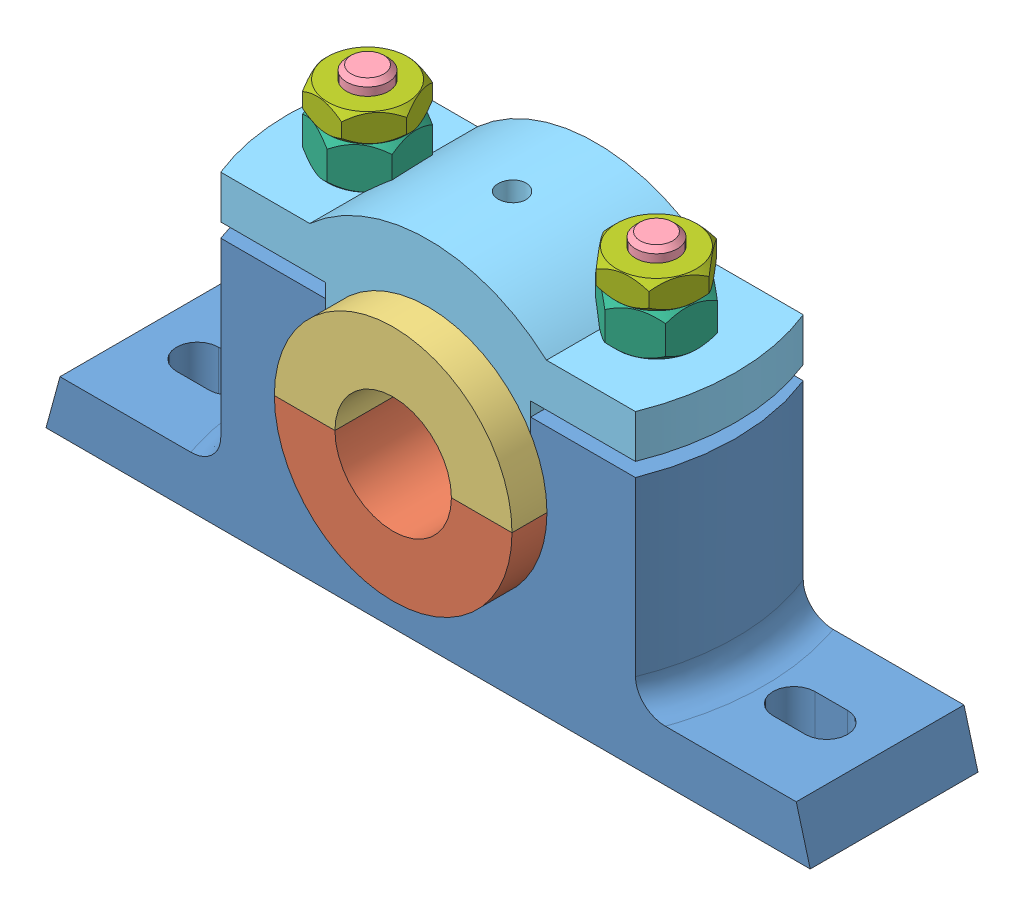
SolidWorks assembly Assem51, configuration Default. Lengths in mm.
Overall size (164 84 51).
10 component instances, 7 part files, 16 mates.
Components (placement in the parent):
- Part2-1: Part2 [Default] at (52.0479 67.0087 143.3422) size (164 54 36)
- Part432-2: Part432 [Default] at (26.5479 105.0087 168.8422) x (0 0 -1) z (-1 0 0) size (51 25.5 51)
- Part43-1: Part43 [Default] at (26.5479 105.0087 117.8422) x (0 0 1) z (-1 0 0) size (51 25.5 51)
- Part44-2: Part44 [Default] at (21.0479 151.0087 143.3422) x (-1 0 0) z (0 -1 0) size (19 19 82)
- Part4-1: Part4 [Default] at (52.0479 105.0087 143.3422) size (96 32 36)
- Part45-2: Part45 [Default] at (21.0479 137.7778 143.3422) x (-0.703417 0 0.710777) z (0 1 0) size (21.7 20.5 9)
- Part45-3: Part45 [Default] at (83.0479 137.7778 143.3422) x (0.703417 0 0.710777) z (0 -1 0) size (21.7 20.5 9)
- Part44-3: Part44 [Default] at (83.0479 151.0087 143.3422) x (-1 0 0) z (0 -1 0) size (19 19 82)
- Part46-1: Part46 [Default] at (21.0479 145.2778 143.3422) x (1 0 0) z (0 1 0) size (21.7 20.5 6)
- Part46-2: Part46 [Default] at (83.0479 145.2778 143.3422) x (-1 0 0) z (0 -1 0) size (21.7 20.5 6)
Mates (geometry in assembly coordinates):
- Lock1: lock: unknown of Part2-1; unknown of Part432-2
- Lock2: lock: unknown of Part2-1; unknown of Part432-2
- Lock5: lock: unknown of Part432-2; unknown of Part43-1
- Concentric6: concentric anti-aligned: circle of Part432-2; cylinder of Part43-1 through (52.0479 122.5087 143.3422) axis (0 1 0) radius 2.5
- Lock8: lock: unknown of Part2-1; unknown of Part44-2
- Concentric15: concentric aligned: cylinder of Part43-1 through (52.0479 105.0087 143.3422) axis (0 0 -1) radius 17.5; cylinder of Part4-1 through (52.0479 105.0087 161.3422) axis (0 0 -1) radius 19
- Concentric18: concentric aligned: cylinder of Part43-1 through (52.0479 105.0087 143.3422) axis (0 0 -1) radius 17.5; cylinder of Part4-1 through (52.0479 105.0087 161.3422) axis (0 0 -1) radius 19
- Concentric19: concentric aligned: cylinder of Part2-1 through (83.0479 121.0087 143.3422) axis (0 1 0) radius 4.5; cylinder of Part4-1 through (83.0479 133.2778 143.3422) axis (0 1 0) radius 4.5
- Concentric20: concentric aligned: cylinder of Part43-1 through (52.0479 105.0087 143.3422) axis (0 0 -1) radius 17.5; cylinder of Part4-1 through (52.0479 105.0087 161.3422) axis (0 0 -1) radius 19
- Lock9: lock: unknown of Part2-1; unknown of Part44-3
- Concentric21: concentric aligned: cylinder of Part2-1 through (83.0479 121.0087 143.3422) axis (0 1 0) radius 4.5; cylinder of Part44-3 through (83.0479 75.0087 143.3422) axis (0 1 0) radius 4.5
- Parallel1: parallel: line of Part2-1 through (31.0479 67.0087 133.3422) axis (0 0 1); line of Part44-2 through (30.5479 69.0087 133.8422) axis (0 0 1)
- Coincident13: coincident anti-aligned: plane of Part4-1 through (106.444 133.2778 161.3422) normal (0 1 0); plane of Part45-3 through (83.0479 133.2778 143.3422) normal (0 -1 0)
- Lock10: lock: unknown of Part45-3; unknown of Part44-3
- Concentric23: concentric aligned: cylinder of Part44-3 through (83.0479 75.0087 143.3422) axis (0 1 0) radius 4.5; cylinder of Part46-2 through (83.0479 142.2778 143.3422) axis (0 1 0) radius 4.5
- Lock11: lock: unknown of Part45-3; unknown of Part46-2
